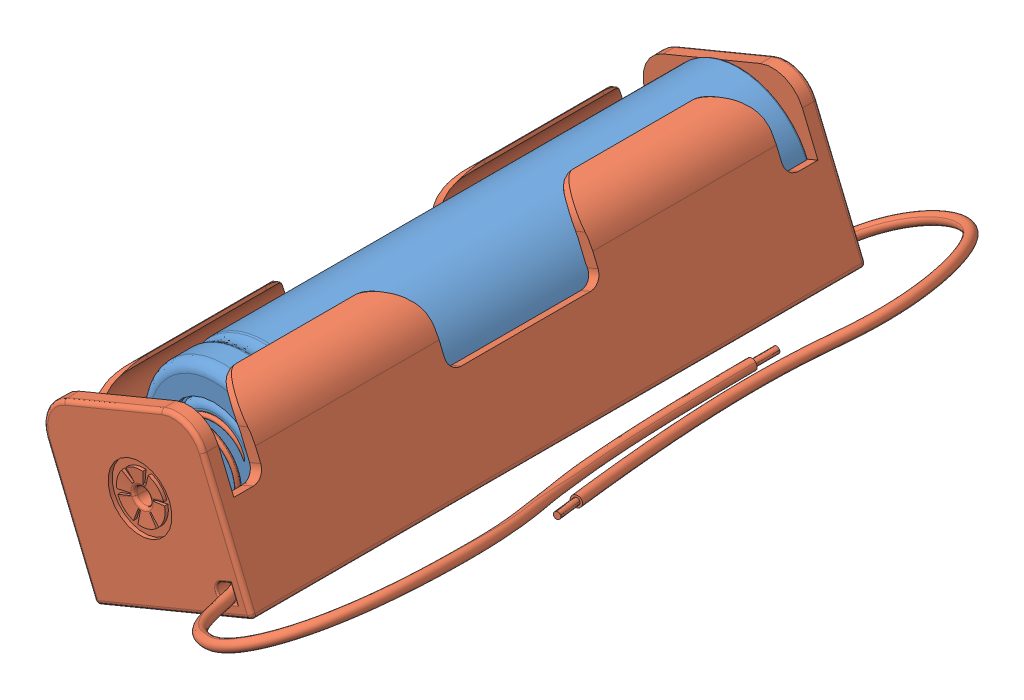
SolidWorks assembly Assem battery, configuration Default. Lengths in mm.
Overall size (45.9 34.33 92.22).
2 component instances, 2 part files, 2 mates.
Components (placement in the parent):
- 18650-1: 18650 [Default] at (12.4817 58.8685 44.9948) x (0 0 1) z (-1 0 0) size (65 18.4 18.4)
- 18650 Battery Holder.step-3: 18650 Battery Holder.step [Default] at (12.8648 57.9447 81.1202) x (-0.923728 -0.383049 0) z (0 0 -1) size (41.39 20 92.22)
Mates (geometry in assembly coordinates):
- Coincident2: coincident anti-aligned: plane of 18650-1 through (12.4817 58.8685 45.0202) normal (0 0 -1); plane of 18650 Battery Holder.step-3 through (15.4164 63.5394 45.0202) normal (0 0 1)
- Concentric3: concentric aligned: circle of 18650-1; circle of 18650 Battery Holder.step-3
